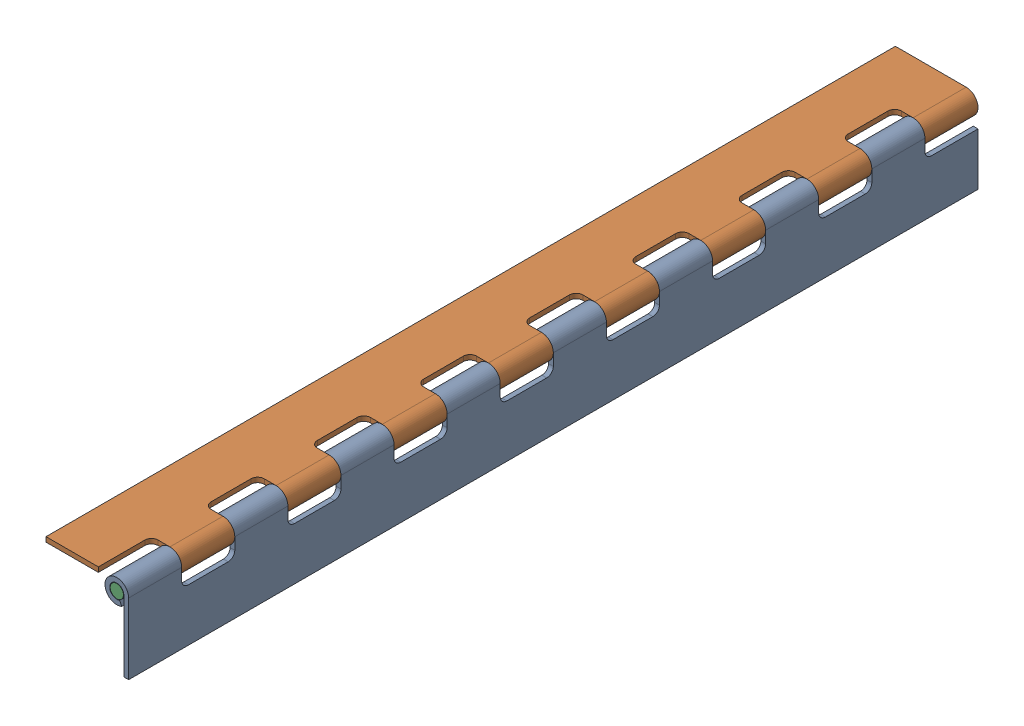
SolidWorks assembly FE-00004-02_, configuration Default. Lengths in mm.
Overall size (39.53 39.53 406.4).
3 component instances, 2 part files, 0 mates.
Components (placement in the parent):
- FE-00004-02A_-1: FE-00004-02A_ [Default] at origin size (11.3 39.53 406.4)
- FE-00004-02A_-2: FE-00004-02A_ [Default] at (-28.5213 28.5213 406.4) x (0 1 0) z (0 0 -1) size (11.3 39.53 406.4)
- FE-00004-02C_-1: FE-00004-02C_ [Default] at (9.0309 7.3635 0) size (6.35 6.35 406.4)
